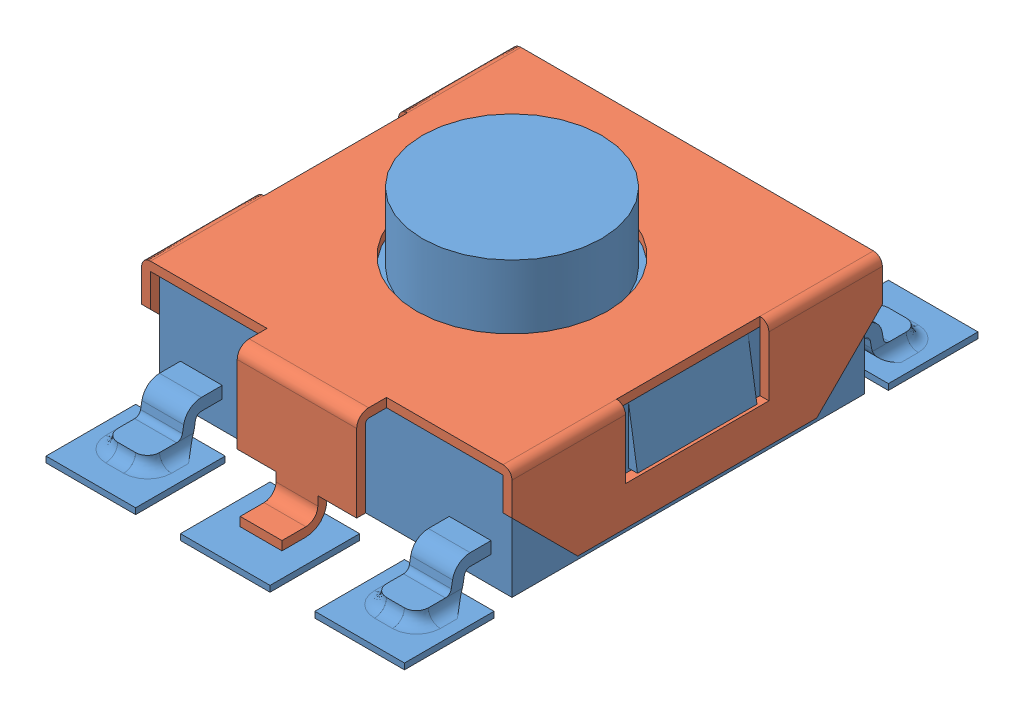
SolidWorks assembly RESET BUTTON, configuration Default. Lengths in mm.
Overall size (6.2 3.1 9.6).
2 component instances, 2 part files, 6 mates.
Components (placement in the parent):
- RESET CORE-1: RESET CORE [Default] at (0 0.1 0) x (-1 0 0) z (0 0 -1) size (6.2 3.1 9.6)
- RESET-1: RESET [Default] at (0 0.1 0) x (0 0 1) z (-1 0 0) size (6.2 1.8 6.2)
Mates (geometry in assembly coordinates):
- Coincident4: coincident anti-aligned: plane of RESET CORE-1 through (0 0.1 0) normal (0 0 -1); plane of assembly
- Coincident5: coincident anti-aligned: plane of RESET CORE-1 through (0 0.1 0) normal (-1 0 0); plane of assembly through (0 0 0) normal (1 0 0)
- Coincident6: coincident anti-aligned: plane of RESET CORE-1 through (0 0 0) normal (0 -1 0); plane of assembly through (0 0 0) normal (0 1 0)
- Coincident7: coincident aligned: plane of RESET-1 through (0 0.1 0) normal (0 0 1); plane of assembly
- Coincident9: coincident anti-aligned: plane of RESET-1 through (0 0.1 0) normal (-1 0 0); plane of assembly through (0 0 0) normal (1 0 0)
- Coincident10: coincident aligned: plane of RESET CORE-1; plane of RESET-1
